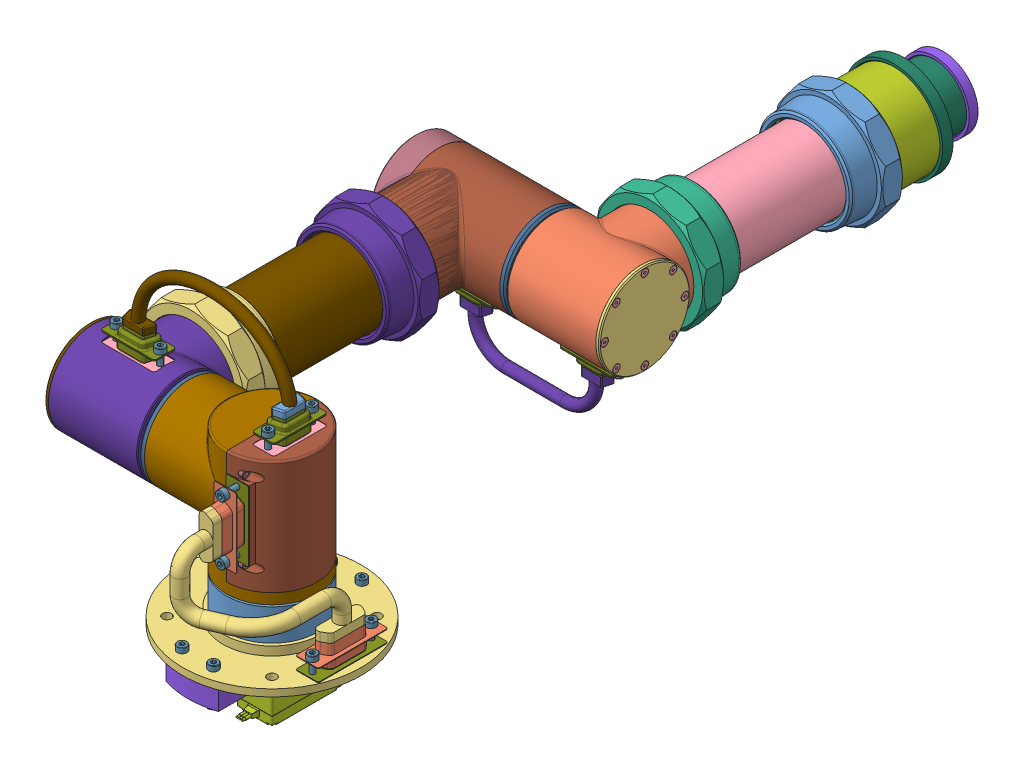
SolidWorks assembly manipulator, configuration По умолчанию. Lengths in mm.
Overall size (186.37 193.67 454.51).
208 component instances, 77 part files, 63 mates.
Components (placement in the parent):
- link_0-1: link_0 [По умолчанию] at origin size (102 73 102)
  - shell_0-2: shell_0 [По умолчанию] x (-1 0 0) z (0 -1 0) size (52 52 23)
  - sleave_external_0-1: sleave_external_0 [00] at (0 12 0) x (0 -1 0) z (0.129917 0 0.991525) size (3 42 42)
  - flange_0-1: flange_0 [По умолчанию] at (0 -4 0) size (102 9 102)
  - shaft_0-1: shaft_0 [00] at (0 -4 0) x (0 -1 0) z (0 0 -1) size (31 32 32)
  - servo_flange-1: servo_flange [По умолчанию] at (0 -1.5 0) x (-0.707107 0 0.707107) z (0.707107 0 0.707107) size (20 4.5 20)
  - screw_M3x8(DIN912)-1: screw_M3x8(DIN912) [По умолчанию] at (4.9497 -6 4.9497) x (-0.866025 0 -0.5) z (0 -1 0) size (4.6 4.6 10)
  - screw_M3x8(DIN912)-2: screw_M3x8(DIN912) [По умолчанию] at (-4.9497 -6 4.9497) x (0.5 0 -0.866025) z (0 -1 0) size (4.6 4.6 10)
  - screw_M3x8(DIN912)-3: screw_M3x8(DIN912) [По умолчанию] at (-4.9497 -6 -4.9497) x (0.866025 0 0.5) z (0 -1 0) size (4.6 4.6 10)
  - screw_M3x8(DIN912)-4: screw_M3x8(DIN912) [По умолчанию] at (4.9497 -6 -4.9497) x (-0.5 0 0.866025) z (0 -1 0) size (4.6 4.6 10)
  - servo_MG995-1: servo_MG995 [По умолчанию] at (0 -46 -10) x (0 0 1) z (0 1 0) size (55.5 20 44.57)
  - servo_lock-1: servo_lock [По умолчанию] at (0 -17 0) x (-1 0 0) z (0 0 -1) size (30 13 96)
  - screw_M4x14(DIN912)-1: screw_M4x14(DIN912) [По умолчанию] at (5 -23 14) x (0.91175 0 0.410745) z (0 -1 0) size (7 7 18)
  - ГайкаM4(DIN936)-1: ГайкаM4(DIN936) [По умолчанию] at (5 -9 14) size (7 2.2 8.08)
  - screw_M4x14(DIN912)-2: screw_M4x14(DIN912) [По умолчанию] at (-5 -23 14) x (0.91175 0 0.410745) z (0 -1 0) size (7 7 18)
  - screw_M4x14(DIN912)-3: screw_M4x14(DIN912) [По умолчанию] at (5 -23 -34) x (0.91175 0 0.410745) z (0 -1 0) size (7 7 18)
  - screw_M4x14(DIN912)-4: screw_M4x14(DIN912) [По умолчанию] at (-5 -23 -34) x (0.91175 0 0.410745) z (0 -1 0) size (7 7 18)
  - ГайкаM4(DIN936)-2: ГайкаM4(DIN936) [По умолчанию] at (-5 -9 14) size (7 2.2 8.08)
  - ГайкаM4(DIN936)-3: ГайкаM4(DIN936) [По умолчанию] at (5 -9 -34) size (7 2.2 8.08)
  - ГайкаM4(DIN936)-4: ГайкаM4(DIN936) [По умолчанию] at (-5 -9 -34) size (7 2.2 8.08)
  - bearing_6905-2RS_0-1: bearing_6905-2RS_0 [00] at (0 21 0) x (0 -1 0) z (-0.000456 0 -1) size (9 42 42)
  - sleave_internal_0-1: sleave_internal_0 [00] at (0 12 0) x (0 -1 0) z (0.154614 0 0.987975) size (3 29 29)
  - bearing_6905-2RS_0-2: bearing_6905-2RS_0 [00] at (0 9 0) x (0 -1 0) z (-0.000456 0 -1) size (9 42 42)
  - circlip for shafts normal_din-1: circlip for shafts normal_din [Circlip DIN 471 - 25 x 1.2] x (0.999946 0 -0.010391) z (0 1 0) size (28.33 31.3 1.2)
  - socket head cap screw_din-1: socket head cap screw_din [DIN 912 M2.5 x 10 --- 10N] at (11.75 -6.5 20.3516) x (0 1 0) z (-0.355215 0 0.934785) size (12.5 4.5 4.5)
  - socket head cap screw_din-2: socket head cap screw_din [DIN 912 M2.5 x 10 --- 10N] at (-11.75 -6.5 20.3516) x (0 1 0) z (-0.987155 0 0.159767) size (12.5 4.5 4.5)
  - socket head cap screw_din-3: socket head cap screw_din [DIN 912 M2.5 x 10 --- 10N] at (-23.5 -6.5 0) x (0 1 0) z (-0.631939 0 -0.775018) size (12.5 4.5 4.5)
  - socket head cap screw_din-4: socket head cap screw_din [DIN 912 M2.5 x 10 --- 10N] at (-11.75 -6.5 -20.3516) x (0 1 0) z (0.355215 0 -0.934785) size (12.5 4.5 4.5)
  - socket head cap screw_din-5: socket head cap screw_din [DIN 912 M2.5 x 10 --- 10N] at (11.75 -6.5 -20.3516) x (0 1 0) z (0.987155 0 -0.159767) size (12.5 4.5 4.5)
  - socket head cap screw_din-6: socket head cap screw_din [DIN 912 M2.5 x 10 --- 10N] at (23.5 -6.5 0) x (0 1 0) z (0.631939 0 0.775018) size (12.5 4.5 4.5)
  - socket head cap screw_din-7: socket head cap screw_din [DIN 912 M3 x 20 --- 20N] at (9 3 42.5) x (0 -1 0) z (1 0 0) size (23 5.5 5.5)
  - hex thin nut gradeb_din-1: hex thin nut gradeb_din [Hexagon Nut ISO 4036 - M3 - N] at (9 -18.8 42.5) x (0.546938 0 -0.837173) z (0 -1 0) size (5.5 6.35 1.8)
  - socket head cap screw_din-8: socket head cap screw_din [DIN 912 M3 x 20 --- 20N] at (9 3 -42.5) x (0 -1 0) z (1 0 0) size (23 5.5 5.5)
  - socket head cap screw_din-9: socket head cap screw_din [DIN 912 M3 x 20 --- 20N] at (-9 3 42.5) x (0 -1 0) z (1 0 0) size (23 5.5 5.5)
  - socket head cap screw_din-10: socket head cap screw_din [DIN 912 M3 x 20 --- 20N] at (-9 3 -42.5) x (0 -1 0) z (1 0 0) size (23 5.5 5.5)
  - hex thin nut gradeb_din-2: hex thin nut gradeb_din [Hexagon Nut ISO 4036 - M3 - N] at (9 -18.8 -42.5) x (0.546938 0 -0.837173) z (0 -1 0) size (5.5 6.35 1.8)
  - hex thin nut gradeb_din-3: hex thin nut gradeb_din [Hexagon Nut ISO 4036 - M3 - N] at (-9 -18.8 42.5) x (0.546938 0 -0.837173) z (0 -1 0) size (5.5 6.35 1.8)
  - hex thin nut gradeb_din-4: hex thin nut gradeb_din [Hexagon Nut ISO 4036 - M3 - N] at (-9 -18.8 -42.5) x (0.546938 0 -0.837173) z (0 -1 0) size (5.5 6.35 1.8)
  - DB15_F-1: DB15_F [По умолчанию] at (38.6 6.31 9.695) x (0 0 -1) z (1 0 0) size (40 15.72 13)
- link_2-1: link_2 [00] at (-56 68 0) x (0 0 -1) z (-1 0 0) size (248.92 91.41 97.96)
  - link_2_part_1-1: link_2_part_1 [00] at origin size (82.24 91.41 89.92)
    - case_2_part_1-1: case_2_part_1 [По умолчанию] at origin size (79.09 52.19 55.06)
    - case_cover_2_part_1-1: case_cover_2_part_1 [По умолчанию] at (0 0 46) size (52 52 2)
    - screw_M2x8(DIN7991)_2_part_1-1: screw_M2x8(DIN7991)_2_part_1 [Default] at (-23 0 46.8) x (0 0 -1) z (1 0 0) size (8 4 4)
    - screw_M2x8(DIN7991)_2_part_1-2: screw_M2x8(DIN7991)_2_part_1 [Default] at (-16.2635 16.2635 46.8) x (0 0 -1) z (1 0 0) size (8 4 4)
    - screw_M2x8(DIN7991)_2_part_1-3: screw_M2x8(DIN7991)_2_part_1 [Default] at (0 23 46.8) x (0 0 -1) z (1 0 0) size (8 4 4)
    - screw_M2x8(DIN7991)_2_part_1-4: screw_M2x8(DIN7991)_2_part_1 [Default] at (16.2635 16.2635 46.8) x (0 0 -1) z (1 0 0) size (8 4 4)
    - screw_M2x8(DIN7991)_2_part_1-5: screw_M2x8(DIN7991)_2_part_1 [Default] at (23 0 46.8) x (0 0 -1) z (1 0 0) size (8 4 4)
    - screw_M2x8(DIN7991)_2_part_1-6: screw_M2x8(DIN7991)_2_part_1 [Default] at (16.2635 -16.2635 46.8) x (0 0 -1) z (1 0 0) size (8 4 4)
    - screw_M2x8(DIN7991)_2_part_1-7: screw_M2x8(DIN7991)_2_part_1 [Default] at (0 -23 46.8) x (0 0 -1) z (1 0 0) size (8 4 4)
    - screw_M2x8(DIN7991)_2_part_1-8: screw_M2x8(DIN7991)_2_part_1 [Default] at (-16.2635 -16.2635 46.8) x (0 0 -1) z (1 0 0) size (8 4 4)
    - bolt_M3x8(DIN912)_2_part_1-1: bolt_M3x8(DIN912)_2_part_1 [По умолчанию] at (10 0 2) size (4.6 4.6 10)
    - bolt_M3x8(DIN912)_2_part_1-3: bolt_M3x8(DIN912)_2_part_1 [По умолчанию] at (0 -10 2) size (4.6 4.6 10)
    - bolt_M3x8(DIN912)_2_part_1-4: bolt_M3x8(DIN912)_2_part_1 [По умолчанию] at (-10 0 2) size (4.6 4.6 10)
    - bolt_M3x8(DIN912)_2_part_1-5: bolt_M3x8(DIN912)_2_part_1 [По умолчанию] at (0 10 2) size (4.6 4.6 10)
    - collet_nut_2_part_1-4: collet_nut_2_part_1 [По умолчанию] at (42.2 0 20.5) x (0 -0.587785 0.809017) z (0 0.809017 0.587785) size (61.55 26.55 68.27)
    - A_DB9-1: A_DB9 [По умолчанию] at (-16.7349 -2.8234 29.5281) x (0 0 -1) z (0 -1 0) size (30.9 12.5 15.5)
  - link_2_part_2-2: link_2_part_2 [00] at (186 0 -1.5) x (0 0 1) z (-0.003987 0.999992 0) size (83.78 107.15 73.54)
    - shaft_2-1: shaft_2 [00] x (1 0 0) z (0 0.707107 0.707107) size (31 32 32)
    - bearing_6905-2RS-1: bearing_6905-2RS [00] at (-25 0 0) size (9 42 42)
    - sleave_internal_2-1: sleave_internal_2 [00] at (-16 0 0) size (3 29 29)
    - sleave_external_2-2: sleave_external_2 [00] at (-16 0 0) size (3 42 42)
    - bearing_6905-2RS-2: bearing_6905-2RS [00] at (-13 0 0) size (9 42 42)
    - servo_flange_2-1: servo_flange_2 [По умолчанию] at (-2.5 0 0) x (0 -1 0) z (0 0 1) size (20 4.5 20)
    - bearing_cover_2-1: bearing_cover_2 [00] at (-28 0 0) x (1 0 0) z (0 0.709921 0.704282) size (3.19 52 52)
    - case_2_part_2-3: case_2_part_2 [00] at (-25 0 0) x (1 0 0) z (0 0.003987 0.999992) size (72 93 52)
    - servo_MG995-2: servo_MG995 [По умолчанию] at (42 -9.9999 0.0399) x (0 0.999992 -0.003987) z (-1 0 0) size (55.5 20 44.57)
    - screw_M2x10(DIN7991)_2_part_2-2: screw_M2x10(DIN7991)_2_part_2 [Default] at (-26.8 22.9998 -0.0917) x (1 0 0) z (0 -0.003987 -0.999992) size (10 4 4)
    - case_cover_2_part_2-2: case_cover_2_part_2 [00] at (22 0 0) x (0 -0.999992 0.003987) z (0 0.003987 0.999992) size (63 17.67 52)
    - servo_lock_2-1: servo_lock_2 [00] at (8 0 0) x (0 -0.003987 -0.999992) z (1 0 0) size (50 59.91 34)
    - bolt_M3x8(DIN912)-1: bolt_M3x8(DIN912) [По умолчанию] at (17 14.0198 4.9441) x (0 -0.003987 -0.999992) z (1 0 0) size (4.6 4.6 10)
    - screw_M2x10(DIN7991)_2_part_2-13: screw_M2x10(DIN7991)_2_part_2 [Default] at (-26.8 16.3282 16.1985) x (1 0 0) z (0 -0.003987 -0.999992) size (10 4 4)
    - screw_M2x10(DIN7991)_2_part_2-14: screw_M2x10(DIN7991)_2_part_2 [Default] at (-26.8 0.0917 22.9998) x (1 0 0) z (0 -0.003987 -0.999992) size (10 4 4)
    - screw_M2x10(DIN7991)_2_part_2-15: screw_M2x10(DIN7991)_2_part_2 [Default] at (-26.8 -16.1985 16.3282) x (1 0 0) z (0 -0.003987 -0.999992) size (10 4 4)
    - screw_M2x10(DIN7991)_2_part_2-16: screw_M2x10(DIN7991)_2_part_2 [Default] at (-26.8 -22.9998 0.0917) x (1 0 0) z (0 -0.003987 -0.999992) size (10 4 4)
    - screw_M2x10(DIN7991)_2_part_2-17: screw_M2x10(DIN7991)_2_part_2 [Default] at (-26.8 -16.3282 -16.1985) x (1 0 0) z (0 -0.003987 -0.999992) size (10 4 4)
    - screw_M2x10(DIN7991)_2_part_2-18: screw_M2x10(DIN7991)_2_part_2 [Default] at (-26.8 -0.0917 -22.9998) x (1 0 0) z (0 -0.003987 -0.999992) size (10 4 4)
    - screw_M2x10(DIN7991)_2_part_2-19: screw_M2x10(DIN7991)_2_part_2 [Default] at (-26.8 16.1985 -16.3282) x (1 0 0) z (0 -0.003987 -0.999992) size (10 4 4)
    - bolt_M3x8(DIN912)-10: bolt_M3x8(DIN912) [По умолчанию] at (2 -7 0) x (0 -0.868012 -0.496543) z (1 0 0) size (4.6 4.6 10)
    - bolt_M3x8(DIN912)-11: bolt_M3x8(DIN912) [По умолчанию] at (2 0 7) x (0 -0.868012 -0.496543) z (1 0 0) size (4.6 4.6 10)
    - bolt_M3x8(DIN912)-12: bolt_M3x8(DIN912) [По умолчанию] at (2 7 0) x (0 -0.868012 -0.496543) z (1 0 0) size (4.6 4.6 10)
    - bolt_M3x8(DIN912)-13: bolt_M3x8(DIN912) [По умолчанию] at (2 0 -7) x (0 -0.868012 -0.496543) z (1 0 0) size (4.6 4.6 10)
    - bolt_M3x8(DIN912)-15: bolt_M3x8(DIN912) [По умолчанию] at (17 13.98 -5.0558) x (0 -0.003987 -0.999992) z (1 0 0) size (4.6 4.6 10)
    - bolt_M3x8(DIN912)-16: bolt_M3x8(DIN912) [По умолчанию] at (17 -33.9798 5.1355) x (0 -0.003987 -0.999992) z (1 0 0) size (4.6 4.6 10)
    - bolt_M3x8(DIN912)-17: bolt_M3x8(DIN912) [По умолчанию] at (17 -34.0197 -4.8644) x (0 -0.003987 -0.999992) z (1 0 0) size (4.6 4.6 10)
    - screw_M2x16(DIN7991)_2_part_2-6: screw_M2x16(DIN7991)_2_part_2 [Default] at (48.3 0.0917 22.9998) x (-1 0 0) z (0 -0.003987 -0.999992) size (16 4 4)
    - screw_M2x16(DIN7991)_2_part_2-7: screw_M2x16(DIN7991)_2_part_2 [Default] at (48.3 16.3282 16.1985) x (-1 0 0) z (0 -0.003987 -0.999992) size (16 4 4)
    - screw_M2x16(DIN7991)_2_part_2-8: screw_M2x16(DIN7991)_2_part_2 [Default] at (48.3 22.9998 -0.0917) x (-1 0 0) z (0 -0.003987 -0.999992) size (16 4 4)
    - screw_M2x16(DIN7991)_2_part_2-9: screw_M2x16(DIN7991)_2_part_2 [Default] at (48.3 16.1985 -16.3282) x (-1 0 0) z (0 -0.003987 -0.999992) size (16 4 4)
    - screw_M2x16(DIN7991)_2_part_2-10: screw_M2x16(DIN7991)_2_part_2 [Default] at (48.3 -0.0917 -22.9998) x (-1 0 0) z (0 -0.003987 -0.999992) size (16 4 4)
    - collet_nut_2_part_2-1: collet_nut_2_part_2 [По умолчанию] at (22 -56.1996 0.2241) x (-1 0 0) z (0 0.003987 0.999992) size (61.55 26.55 68.27)
    - circlip for shafts normal_din-1: circlip for shafts normal_din [Circlip DIN 471 - 25 x 1.2] at (-4 0 0) x (0 0.144431 0.989515) z (-1 0 0) size (28.33 31.3 1.2)
    - A_DB9-1: A_DB9 [По умолчанию] at (5.9719 -16.7195 3.89) x (1 0 0) z (0 0.003987 0.999992) size (30.9 12.5 15.5)
  - pipe_2-1: pipe_2 [По умолчанию] at (146 0 20.5) x (-1 0 0) z (0 -0.924225 -0.381849) size (120 45 45)
  - провод^link_2-1: провод^link_2 [По умолчанию] at origin size (210 37.6 33.75) (virtual)
- link_3-1: link_3 [00] at (-20.5 68 -186) x (0 0 -1) z (1 0 0) size (231.3 129.82 129.82)
  - link_3_part_1-1: link_3_part_1 [00] at origin size (82.24 68.27 61.55)
    - case_3_part_1-2: case_3_part_1 [По умолчанию] at origin size (79.09 52.19 55.06)
    - case_cover_3_part_1-1: case_cover_3_part_1 [По умолчанию] at (0 0 46) size (52 52 2)
    - screw_M2x8(DIN7991)_3_part_1-1: screw_M2x8(DIN7991)_3_part_1 [Default] at (-23 0 46.8) x (0 0 -1) z (1 0 0) size (8 4 4)
    - screw_M2x8(DIN7991)_3_part_1-2: screw_M2x8(DIN7991)_3_part_1 [Default] at (-16.2635 16.2635 46.8) x (0 0 -1) z (1 0 0) size (8 4 4)
    - screw_M2x8(DIN7991)_3_part_1-3: screw_M2x8(DIN7991)_3_part_1 [Default] at (0 23 46.8) x (0 0 -1) z (1 0 0) size (8 4 4)
    - screw_M2x8(DIN7991)_3_part_1-4: screw_M2x8(DIN7991)_3_part_1 [Default] at (16.2635 16.2635 46.8) x (0 0 -1) z (1 0 0) size (8 4 4)
    - screw_M2x8(DIN7991)_3_part_1-5: screw_M2x8(DIN7991)_3_part_1 [Default] at (23 0 46.8) x (0 0 -1) z (1 0 0) size (8 4 4)
    - screw_M2x8(DIN7991)_3_part_1-6: screw_M2x8(DIN7991)_3_part_1 [Default] at (16.2635 -16.2635 46.8) x (0 0 -1) z (1 0 0) size (8 4 4)
    - screw_M2x8(DIN7991)_3_part_1-7: screw_M2x8(DIN7991)_3_part_1 [Default] at (0 -23 46.8) x (0 0 -1) z (1 0 0) size (8 4 4)
    - screw_M2x8(DIN7991)_3_part_1-8: screw_M2x8(DIN7991)_3_part_1 [Default] at (-16.2635 -16.2635 46.8) x (0 0 -1) z (1 0 0) size (8 4 4)
    - bolt_M3x8(DIN912)_3_part_1-1: bolt_M3x8(DIN912)_3_part_1 [По умолчанию] at (10 0 2) size (4.6 4.6 10)
    - bolt_M3x8(DIN912)_3_part_1-2: bolt_M3x8(DIN912)_3_part_1 [По умолчанию] at (0 -10 2) size (4.6 4.6 10)
    - bolt_M3x8(DIN912)_3_part_1-3: bolt_M3x8(DIN912)_3_part_1 [По умолчанию] at (-10 0 2) size (4.6 4.6 10)
    - bolt_M3x8(DIN912)_3_part_1-4: bolt_M3x8(DIN912)_3_part_1 [По умолчанию] at (0 10 2) size (4.6 4.6 10)
    - A_DB9-2: A_DB9 [По умолчанию] at (-16.7349 -3.8234 29.5281) x (0 0 -1) z (0 -1 0) size (30.9 12.5 15.5)
    - collet_nut_3_part_1-2: collet_nut_3_part_1 [По умолчанию] at (42.2 0 20.5) x (0 0 -1) z (0 -1 0) size (61.55 26.55 68.27)
  - link_3_part_2-1: link_3_part_2 [По умолчанию] at (135 0 20.5) x (0 0.707107 -0.707107) z (1 0 0) size (91.8 91.8 86.74)
    - case_3_part_2-2: case_3_part_2 [По умолчанию] at origin size (52.23 52.12 50.29)
    - case_cover_3_part_2-1: case_cover_3_part_2 [По умолчанию] at (0 0 60.3) x (-0.707107 -0.707107 0) z (0 0 1) size (40 40 5)
    - servo_MG90S-1: servo_MG90S [Default] at (-5.25 0 12) x (1 0 0) z (0 -1 0) size (32.2 32.5 12.4)
    - servo_flange_3-2: servo_flange_3 [По умолчанию] at (0 0 45.3) x (0.074504 -0.997221 0) z (0 0 -1) size (17 17 9)
    - bearing_6803-1: bearing_6803 [По умолчанию] at (0 0 55.3) x (0.713069 0.701094 0) z (0 0 1) size (26 26 5)
    - bearing_6803-2: bearing_6803 [По умолчанию] at (0 0 53.8) x (-0.923728 -0.383049 0) z (0 0 -1) size (26 26 5)
    - shaft_3_part_2-1: shaft_3_part_2 [По умолчанию] at (0 0 45.3) x (-0.074504 0.997221 0) z (0.997221 0.074504 0) size (20 25 20)
    - ext_sleeve_3_part_2-1: ext_sleeve_3_part_2 [По умолчанию] at (0 0 55.3) x (-0.923728 -0.383049 0) z (0 0 -1) size (26 26 1.5)
    - int_sleeve_3_part_2-1: int_sleeve_3_part_2 [По умолчанию] at (0 0 55.3) x (-0.923728 -0.383049 0) z (0 0 -1) size (19 19 1.5)
    - nozzle_3_part_2-1: nozzle_3_part_2 [По умолчанию] at (0 0 37) x (0.707107 0.707107 0) z (0.707107 -0.707107 0) size (56 25.3 56)
    - screw_M2x8(DIN963)-1: screw_M2x8(DIN963) [По умолчанию] at (-15.5563 -15.5563 40.6206) x (0 0 -1) z (-0.707107 -0.707107 0) size (8 3.8 3.77)
    - screw_M2x8(DIN963)-5: screw_M2x8(DIN963) [По умолчанию] at (10.9602 10.9602 62.9206) x (0 0 -1) z (0.707107 0.707107 0) size (8 3.8 3.77)
    - nut_M1.6(DIN934)-1: nut_M1.6(DIN934) [По умолчанию] at (-19.1 0 34.8) x (1 0 0) z (0 0 -1) size (2.95 3.41 1.3)
    - screw_M1.6x10(DIN921)-1: screw_M1.6x10(DIN921) [По умолчанию] at (-19.1 0 24.9) x (0 0 1) z (-1 0 0) size (11.6 3 3)
    - nut_M1.6(DIN934)-2: nut_M1.6(DIN934) [По умолчанию] at (8.6 0 34.8) x (1 0 0) z (0 0 -1) size (2.95 3.41 1.3)
    - screw_M1.6x10(DIN921)-2: screw_M1.6x10(DIN921) [По умолчанию] at (8.6 0 24.9) x (0 0 1) z (-0.053634 0.998561 0) size (11.6 3 3)
    - screw_M2x8(DIN963)-2: screw_M2x8(DIN963) [По умолчанию] at (-15.5563 15.5563 40.6206) x (0 0 -1) z (-0.707107 0.707107 0) size (8 3.8 3.77)
    - screw_M2x8(DIN963)-3: screw_M2x8(DIN963) [По умолчанию] at (15.5563 15.5563 40.6206) x (0 0 -1) z (0.707107 0.707107 0) size (8 3.8 3.77)
    - screw_M2x8(DIN963)-4: screw_M2x8(DIN963) [По умолчанию] at (15.5563 -15.5563 40.6206) x (0 0 -1) z (0.707107 -0.707107 0) size (8 3.8 3.77)
    - screw_M2x8(DIN963)-6: screw_M2x8(DIN963) [По умолчанию] at (10.9602 -10.9602 62.9206) x (0 0 -1) z (0.707107 -0.707107 0) size (8 3.8 3.77)
    - screw_M2x8(DIN963)-7: screw_M2x8(DIN963) [По умолчанию] at (-10.9602 -10.9602 62.9206) x (0 0 -1) z (-0.707107 -0.707107 0) size (8 3.8 3.77)
    - screw_M2x8(DIN963)-8: screw_M2x8(DIN963) [По умолчанию] at (-10.9602 10.9602 62.9206) x (0 0 -1) z (-0.707107 0.707107 0) size (8 3.8 3.77)
    - collet_nut_3_part_2-2: collet_nut_3_part_2 [По умолчанию] at (0 0 -2.4) x (-0.707107 0.707107 0) z (-0.707107 -0.707107 0) size (61.55 26.55 68.27)
    - Деталь1^link_3_part_2-1: Деталь1^link_3_part_2 [По умолчанию] at origin (virtual)
    - hex bolt gradeab_din-1: hex bolt gradeab_din [DIN EN 24014 - M2 x 16 x 10-N] at (-0.447 5.9833 41.9) x (0 0 1) z (-0.964999 -0.262255 0) size (17.4 4.62 4)
    - hex bolt gradeab_din-2: hex bolt gradeab_din [DIN EN 24014 - M2 x 16 x 10-N] at (5.9833 0.447 41.9) x (0 0 1) z (-0.262255 0.964999 0) size (17.4 4.62 4)
    - hex bolt gradeab_din-3: hex bolt gradeab_din [DIN EN 24014 - M2 x 16 x 10-N] at (0.447 -5.9833 41.9) x (0 0 1) z (0.964999 0.262255 0) size (17.4 4.62 4)
    - hex bolt gradeab_din-4: hex bolt gradeab_din [DIN EN 24014 - M2 x 16 x 10-N] at (-5.9833 -0.447 41.9) x (0 0 1) z (0.262255 -0.964999 0) size (17.4 4.62 4)
    - retaining_ring-1: retaining_ring [По умолчанию] at (0 0 47.2) size (19 21 1.5)
  - pipe_3-1: pipe_3 [По умолчанию] at (26 0 20.5) x (1 0 0) z (0 -0.068443 0.997655) size (120 45 45)
  - Деталь1^link_3-1: Деталь1^link_3 [По умолчанию] at origin size (155.92 29.47 12.17) (virtual)
- link_1-2: link_1 [00] at (26.6423 95 0) size (79 90.5 58.36)
  - shaft_1-1: shaft_1 [00] at (-48.6423 -27 0) x (1 0 0) z (0 0.707107 0.707107) size (31 32 32)
  - servo_flange-1: servo_flange [По умолчанию] at (-51.1423 -27 0) x (0 1 0) z (0 0 -1) size (20 4.5 20)
  - bearing_6905-2RS-1: bearing_6905-2RS [00] at (-73.6423 -27 0) size (9 42 42)
  - bearing_6905-2RS-2: bearing_6905-2RS [00] at (-61.6423 -27 0) size (9 42 42)
  - sleave_external_1-1: sleave_external_1 [00] at (-64.6423 -27 0) size (3 42 42)
  - sleave_internal_1-1: sleave_internal_1 [00] at (-64.6423 -27 0) size (3 29 29)
  - case_1-1: case_1 [По умолчанию] at (-26.6423 -71 0) x (0 0 -1) z (1 0 0) size (52 71.51 73)
  - servo_MG995-1: servo_MG995 [По умолчанию] at (-6.1423 -37 0) x (0 1 0) z (-1 0 0) size (55.5 20 44.57)
  - bearing_cover_1-1: bearing_cover_1 [00] at (-76.6423 -27 0) x (1 0 0) z (0 -1 0) size (3.19 52 52)
  - case_cover_1-2: case_cover_1 [По умолчанию] at (-26.6423 -65 0) x (0 0 -1) z (1 0 0) size (52 65 27.19)
  - slotted countersunk flat head screw_iso-39: slotted countersunk flat head screw_iso [ISO 2009 - M2 x 8 - 8N] at (-76.6423 -27 23) x (1 0 0) z (0 -0.076481 0.997071) size (8 3.8 3.77)
  - slotted countersunk flat head screw_iso-40: slotted countersunk flat head screw_iso [ISO 2009 - M2 x 8 - 8N] at (-76.6423 -43.2635 16.2635) x (1 0 0) z (0 -0.759116 0.650956) size (8 3.8 3.77)
  - slotted countersunk flat head screw_iso-41: slotted countersunk flat head screw_iso [ISO 2009 - M2 x 8 - 8N] at (-76.6423 -50 0) x (1 0 0) z (0 -0.997071 -0.076481) size (8 3.8 3.77)
  - slotted countersunk flat head screw_iso-42: slotted countersunk flat head screw_iso [ISO 2009 - M2 x 8 - 8N] at (-76.6423 -43.2635 -16.2635) x (1 0 0) z (0 -0.650956 -0.759116) size (8 3.8 3.77)
  - slotted countersunk flat head screw_iso-43: slotted countersunk flat head screw_iso [ISO 2009 - M2 x 8 - 8N] at (-76.6423 -27 -23) x (1 0 0) z (0 0.076481 -0.997071) size (8 3.8 3.77)
  - slotted countersunk flat head screw_iso-44: slotted countersunk flat head screw_iso [ISO 2009 - M2 x 8 - 8N] at (-76.6423 -10.7365 -16.2635) x (1 0 0) z (0 0.759116 -0.650956) size (8 3.8 3.77)
  - slotted countersunk flat head screw_iso-45: slotted countersunk flat head screw_iso [ISO 2009 - M2 x 8 - 8N] at (-76.6423 -4 0) x (1 0 0) z (0 0.997071 0.076481) size (8 3.8 3.77)
  - slotted countersunk flat head screw_iso-46: slotted countersunk flat head screw_iso [ISO 2009 - M2 x 8 - 8N] at (-76.6423 -10.7365 16.2635) x (1 0 0) z (0 0.650956 0.759116) size (8 3.8 3.77)
  - socket head cap screw_iso-25: socket head cap screw_iso [ISO 4762 M2.5 x 10 - 10N] at (-18.1423 -8.5 23) x (-1 0 0) z (0 -0.877208 -0.48011) size (12.5 4.5 4.5)
  - socket head cap screw_iso-29: socket head cap screw_iso [ISO 4762 M2.5 x 10 - 10N] at (-18.1423 -53.5 23) x (-1 0 0) z (0 -0.877208 -0.48011) size (12.5 4.5 4.5)
  - socket head cap screw_iso-27: socket head cap screw_iso [ISO 4762 M2.5 x 10 - 10N] at (-18.1423 -8.5 -23) x (-1 0 0) z (0 -0.877208 -0.48011) size (12.5 4.5 4.5)
  - socket head cap screw_iso-28: socket head cap screw_iso [ISO 4762 M2.5 x 10 - 10N] at (-18.1423 -53.5 -23) x (-1 0 0) z (0 -0.877208 -0.48011) size (12.5 4.5 4.5)
  - socket head cap screw_iso-20: socket head cap screw_iso [ISO 4762 M3 x 8 - 8N] at (-30.1423 -13 5) x (-1 0 0) z (0 0.270929 0.962599) size (11 5.5 5.5)
  - socket head cap screw_iso-24: socket head cap screw_iso [ISO 4762 M3 x 8 - 8N] at (-30.1423 -61 5) x (-1 0 0) z (0 0.270929 0.962599) size (11 5.5 5.5)
  - socket head cap screw_iso-22: socket head cap screw_iso [ISO 4762 M3 x 8 - 8N] at (-30.1423 -13 -5) x (-1 0 0) z (0 0.270929 0.962599) size (11 5.5 5.5)
  - socket head cap screw_iso-23: socket head cap screw_iso [ISO 4762 M3 x 8 - 8N] at (-30.1423 -61 -5) x (-1 0 0) z (0 0.270929 0.962599) size (11 5.5 5.5)
  - socket head cap screw_iso-4: socket head cap screw_iso [ISO 4762 M3 x 8 - 8N] at (-45.6423 -27 7) x (-1 0 0) z (0 0.294157 -0.955757) size (11 5.5 5.5)
  - socket head cap screw_iso-5: socket head cap screw_iso [ISO 4762 M3 x 8 - 8N] at (-45.6423 -34 0) x (-1 0 0) z (0 0.955757 0.294157) size (11 5.5 5.5)
  - socket head cap screw_iso-6: socket head cap screw_iso [ISO 4762 M3 x 8 - 8N] at (-45.6423 -27 -7) x (-1 0 0) z (0 -0.294157 0.955757) size (11 5.5 5.5)
  - socket head cap screw_iso-7: socket head cap screw_iso [ISO 4762 M3 x 8 - 8N] at (-45.6423 -20 0) x (-1 0 0) z (0 -0.955757 -0.294157) size (11 5.5 5.5)
  - circlip for shafts normal_din-1: circlip for shafts normal_din [Circlip DIN 471 - 25 x 1.2] at (-53.1423 -27 0) x (0 0 -1) z (-1 0 0) size (28.33 31.3 1.2) (hidden)
  - A_DB9-1: A_DB9 [По умолчанию] at (0.3425 -22.1766 9.0281) x (0 0 -1) z (0 1 0) size (30.9 12.5 15.5)
  - socket countersunk head screw_din-1: socket countersunk head screw_din [DIN 7991 - M3 x 20 --- 16.8N] at (-16.6423 -65 0) x (0 -1 0) z (-0.98859 0 0.150633) size (20 5.7 5.7)
  - socket countersunk head screw_din-6: socket countersunk head screw_din [DIN 7991 - M3 x 20 --- 16.8N] at (-26.6423 -65 -10) x (0 -1 0) z (0.150633 0 0.98859) size (20 5.7 5.7)
  - socket countersunk head screw_din-3: socket countersunk head screw_din [DIN 7991 - M3 x 20 --- 16.8N] at (-36.6423 -65 0) x (0 -1 0) z (0.98859 0 -0.150633) size (20 5.7 5.7)
  - socket countersunk head screw_din-4: socket countersunk head screw_din [DIN 7991 - M3 x 20 --- 16.8N] at (-26.6423 -65 10) x (0 -1 0) z (-0.150633 0 -0.98859) size (20 5.7 5.7)
  - DB15_F-1: DB15_F [По умолчанию] at (-21.5423 -40.695 32.31) x (0 1 0) z (1 0 0) size (40 15.72 13)
  - провода^link_1-1: провода^link_1 [По умолчанию] at origin size (23.78 38.41 28.01) (virtual)
- A_DB9 - MALE-1: A_DB9 - MALE [По умолчанию] at (-9.0281 14.4234 -169.2651) x (1 0 0) z (0 1 0) size (30.9 12.5 15.5)
- A_DB9 - MALE-2: A_DB9 - MALE [По умолчанию] at (-78.5281 14.4234 -169.2651) x (1 0 0) z (0 1 0) size (30.9 12.5 15.5)
- провод 2-3^manipulator-1: провод 2-3^manipulator [По умолчанию] at origin size (84.34 28 6.5) (virtual)
- socket head cap screw_din-10: socket head cap screw_din [DIN 912 M3 x 16 --- 16N] at (12.5 32.6 -186) x (0 1 0) z (-0.333637 0 0.942702) size (19 5.5 5.5)
- socket head cap screw_din-11: socket head cap screw_din [DIN 912 M3 x 16 --- 16N] at (-12.5 32.6 -186) x (0 1 0) z (-0.85276 0 0.522303) size (19 5.5 5.5)
- socket head cap screw_din-12: socket head cap screw_din [DIN 912 M3 x 16 --- 16N] at (-57 32.6 -186) x (0 1 0) z (-0.094976 0 0.99548) size (19 5.5 5.5)
- socket head cap screw_din-13: socket head cap screw_din [DIN 912 M3 x 16 --- 16N] at (-82 32.6 -186) x (0 1 0) z (-0.517198 0 0.855866) size (19 5.5 5.5)
- A_DB9 - MALE-3: A_DB9 - MALE [По умолчанию] at (-67.4719 120.5766 16.7349) x (-1 0 0) z (0 -1 0) size (30.9 12.5 15.5)
- A_DB9 - MALE-4: A_DB9 - MALE [По умолчанию] at (26.9849 122.5766 -9.0281) x (0 0 1) z (0 -1 0) size (30.9 12.5 15.5)
- wire_1-1: wire_1 [По умолчанию] at (-76.5 109.1 0) x (-1 0 0) z (0 -1 0) size (97.59 6.5 42.57)
- connector_1-1: connector_1 [По умолчанию] at (10.25 111.1 0) x (0 0 1) z (0 -1 0) size (15.19 6.5 4)
- socket head cap screw_din-6: socket head cap screw_din [DIN 912 M3 x 16 --- 16N] at (-89 102.4 0) x (0 -1 0) z (0.447853 0 0.894107) size (19 5.5 5.5)
- socket head cap screw_din-7: socket head cap screw_din [DIN 912 M3 x 16 --- 16N] at (-64 102.4 0) x (0 -1 0) z (0.937749 0 0.347314) size (19 5.5 5.5)
- socket head cap screw_din-8: socket head cap screw_din [DIN 912 M3 x 16 --- 16N] at (10.25 104.4 12.5) x (0 -1 0) z (0.754954 0 0.655778) size (19 5.5 5.5)
- socket head cap screw_din-9: socket head cap screw_din [DIN 912 M3 x 16 --- 16N] at (10.25 104.4 -12.5) x (0 -1 0) z (0.999036 0 0.043895) size (19 5.5 5.5)
- DB15_M-3: DB15_M [По умолчанию] at (5.08 54.155 39.209) x (0 1 0) z (-1 0 0) size (40 15.86 13)
- DB15_M-4: DB15_M [По умолчанию] at (38.58 13.209 9.835) x (0 0 -1) z (-1 0 0) size (40 15.86 13)
- socket head cap screw_din-3: socket head cap screw_din [DIN 912 M3 x 16 --- 16N] at (6.5 80.82 36.309) x (0 0 -1) z (0.56271 -0.826654 0) size (19 5.5 5.5)
- socket head cap screw_din-4: socket head cap screw_din [DIN 912 M3 x 16 --- 16N] at (6.5 47.17 36.309) x (0 0 -1) z (0.813575 0.581461 0) size (19 5.5 5.5)
- провод 0-1^manipulator-1: провод 0-1^manipulator [По умолчанию] at origin size (41.5 63.24 75.67) (virtual)
- socket head cap screw_din-14: socket head cap screw_din [DIN 912 M3 x 16 --- 16N] at (40 10.309 -16.83) x (0 -1 0) z (0.769672 0 0.638439) size (19 5.5 5.5)
- socket head cap screw_din-15: socket head cap screw_din [DIN 912 M3 x 16 --- 16N] at (40 10.309 16.82) x (0 -1 0) z (0.892194 0 0.451653) size (19 5.5 5.5)
- hex thin nut chamfered gradeab_din-1: hex thin nut chamfered gradeab_din [Hexagon Thin Nut ISO 4035 - M3 - N] at (40 -5.8 16.82) x (0.812608 0 -0.582811) z (0 -1 0) size (5.5 6.35 1.8)
- hex thin nut chamfered gradeab_din-2: hex thin nut chamfered gradeab_din [Hexagon Thin Nut ISO 4035 - M3 - N] at (40 -5.8 -16.83) x (0.394981 0 -0.918689) z (0 -1 0) size (5.5 6.35 1.8)
Mates (geometry in assembly coordinates):
- Концентричный4: concentric anti-aligned: cylinder of link_2-1/link_2_part_2-2/case_2_part_2-3 through (-29.5 68 -186) axis (1 0 0) radius 26; cylinder of link_3-1/link_3_part_1-1/case_3_part_1-2 through (25.5 68 -186) axis (-1 0 0) radius 26
- Совпадение9: coincident anti-aligned: plane of link_2-1/link_2_part_2-2/shaft_2-1 through (-23.5 79.2685 -197.3587) normal (1 0 0); plane of link_3-1/link_3_part_1-1/case_3_part_1-2 through (-23.5 68 -186) normal (-1 0 0)
- Концентричный5: concentric anti-aligned: cylinder of link_0-1/shell_0-2 through (0 0 0) axis (0 -1 0) radius 26; cylinder of link_1-2/case_1-1 through (0 97.6815 0) axis (0 1 0) radius 26
- Концентричный6: concentric aligned: cylinder of link_2-1/link_2_part_1-1/case_2_part_1-1 through (-102 68 0) axis (1 0 0) radius 26; cylinder of link_1-2/case_1-1 through (-47 68 0) axis (1 0 0) radius 26
- Совпадение10: coincident anti-aligned: plane of link_0-1/shaft_0-1 through (-16 27 0) normal (0 1 0); plane of link_1-2/case_1-1 through (0 27 0) normal (0 -1 0)
- Совпадение11: coincident anti-aligned: plane of link_2-1/link_2_part_1-1/case_2_part_1-1 through (-53 68 0) normal (1 0 0); plane of link_1-2/shaft_1-1 through (-53 79.3137 -11.3137) normal (-1 0 0)
- Угол1: planar angle aligned: axis of link_1-2/case_1-1 through (-52.5586 68 0) axis (1 0 0); line of link_0-1/servo_lock-1 through (-15 -17 -45.5961) axis (0 0 1)
- Угол2: planar angle aligned: axis of link_2-1/pipe_2-1 through (-76.5 68 -26) axis (0 0 -1); axis of link_1-2/case_cover_1-2 through (0 84 0) axis (0 -1 0)
- Угол3: planar angle anti-aligned: axis of link_2-1/pipe_2-1 through (-76.5 68 -26) axis (0 0 -1); axis of link_3-1/pipe_3-1 through (0 68 -332) axis (0 0 1)
- Совпадение14: coincident anti-aligned: plane of link_3-1/link_3_part_1-1/A_DB9-2 through (0 36.5 -186) normal (0 -1 0); plane of A_DB9 - MALE-1 through (-8.8065 36.5 -189.275) normal (0 1 0)
- Совпадение17: coincident anti-aligned: plane of link_2-1/link_2_part_2-2/A_DB9-1 through (-69.5 36.5 -186) normal (0 -1 0); plane of A_DB9 - MALE-2 through (-78.3065 36.5 -189.275) normal (0 1 0)
- Совпадение25: coincident anti-aligned: plane of A_DB9 - MALE-1 through (0 29.9 -186) normal (0 -1 0); plane of ? through (-68.4582 29.9 -185.4704) normal (0 1 0)
- Совпадение26: coincident anti-aligned: plane of A_DB9 - MALE-1 through (0 29.9 -186) normal (0 -1 0); plane of ? through (1.0949 29.9 -186.1438) normal (0 1 0)
- Совпадение29: coincident anti-aligned: plane of link_2-1/link_2_part_1-1/A_DB9-1 through (-76.5 98.5 0) normal (0 1 0); plane of A_DB9 - MALE-3 through (-67.6935 98.5 -3.275) normal (0 -1 0)
- Совпадение32: coincident anti-aligned: plane of link_1-2/A_DB9-1 through (10.25 100.5 0) normal (0 1 0); plane of A_DB9 - MALE-4 through (6.975 100.5 -8.8065) normal (0 -1 0)
- Совпадение34: coincident anti-aligned: plane of A_DB9 - MALE-3 through (-76.5 105.1 0) normal (0 1 0); plane of wire_1-1 through (-76.5 105.1 0) normal (0 -1 0)
- Ширина1: width anti-aligned: plane of wire_1-1 through (-68.6783 105.1 -3.25) normal (0.965926 0 0.258819); plane of wire_1-1 through (-82.58 105.1 3.25) normal (-0.965926 0 0.258819); plane of A_DB9 - MALE-3 through (-82.8479 99 1.7009) normal (-0.965926 0 0.258819); plane of A_DB9 - MALE-3 through (-70.1521 99 1.7009) normal (0.965926 0 0.258819)
- Совпадение37: coincident aligned: plane of A_DB9 - MALE-3 through (-76.5 99 -3.25) normal (0 0 -1); plane of wire_1-1 through (-84.3217 105.1 -3.25) normal (0 0 -1)
- Совпадение39: coincident anti-aligned: plane of A_DB9 - MALE-4 through (10.25 107.1 0) normal (0 1 0); plane of connector_1-1 through (10.25 107.1 0) normal (0 -1 0)
- Совпадение40: coincident aligned: plane of A_DB9 - MALE-4 through (13.5 101 0) normal (1 0 0); plane of connector_1-1 through (13.5 107.1 -6.08) normal (1 0 0)
- Ширина2: width anti-aligned: plane of connector_1-1 through (13.5 107.1 6.08) normal (0.258819 0 0.965926); plane of connector_1-1 through (7 107.1 -7.8217) normal (0.258819 0 -0.965926); plane of A_DB9 - MALE-4 through (11.9509 101 -6.3479) normal (0.258819 0 -0.965926); plane of A_DB9 - MALE-4 through (11.9509 101 6.3479) normal (0.258819 0 0.965926)
- Концентричный8: concentric aligned: circle of link_1-2/A_DB9-1; circle of A_DB9 - MALE-4
- Концентричный9: concentric aligned: cylinder of link_1-2/A_DB9-1 through (10.25 94.8 -12.5) axis (0 -1 0) radius 1.55; circle of A_DB9 - MALE-4
- Концентричный10: concentric aligned: circle of link_2-1/link_2_part_1-1/A_DB9-1; circle of A_DB9 - MALE-3
- Концентричный11: concentric aligned: circle of link_2-1/link_2_part_1-1/A_DB9-1; circle of A_DB9 - MALE-3
- Концентричный12: concentric aligned: circle of link_3-1/link_3_part_1-1/A_DB9-2; circle of A_DB9 - MALE-1
- Концентричный13: concentric aligned: circle of link_3-1/link_3_part_1-1/A_DB9-2; circle of A_DB9 - MALE-1
- Концентричный14: concentric aligned: circle of link_2-1/link_2_part_2-2/A_DB9-1; circle of A_DB9 - MALE-2
- Концентричный15: concentric aligned: circle of link_2-1/link_2_part_2-2/A_DB9-1; circle of A_DB9 - MALE-2
- Концентричный19: concentric aligned: cylinder of link_1-2/DB15_F-1 through (6.5 80.82 32.31) axis (0 0 -1) radius 1.4; cylinder of DB15_M-3 through (6.5 80.82 39.209) axis (0 0 -1) radius 1.4
- Параллельность3: parallel aligned: plane of link_1-2/DB15_F-1 through (13.02 83 26.2) normal (1 0 0); plane of DB15_M-3 through (13 43.995 32.909) normal (1 0 0)
- Совпадение44: coincident anti-aligned: plane of link_1-2/DB15_F-1 through (5.1 73.695 32.309) normal (0 0 1); plane of DB15_M-3 through (5.08 73.835 32.309) normal (0 0 -1)
- Концентричный22: concentric anti-aligned: cylinder of DB15_M-3 through (6.5 80.82 39.209) axis (0 0 -1) radius 1.4; cylinder of socket head cap screw_din-3 through (6.5 80.82 68.059) axis (0 0 1) radius 1.5
- Совпадение45: coincident anti-aligned: plane of DB15_M-3 through (0 43.995 33.309) normal (0 0 1); plane of socket head cap screw_din-3 through (8.7733 82.3675 33.309) normal (0 0 -1)
- Концентричный23: concentric anti-aligned: cylinder of DB15_M-3 through (6.5 47.17 39.209) axis (0 0 -1) radius 1.4; cylinder of socket head cap screw_din-4 through (6.5 47.17 68.059) axis (0 0 1) radius 1.5
- Совпадение46: coincident aligned: plane of DB15_M-3 through (0 43.995 33.309) normal (0 0 1); circle of socket head cap screw_din-4
- Концентричный24: concentric anti-aligned: cylinder of A_DB9 - MALE-3 through (-89 99.4 0) axis (0 -1 0) radius 1.55; cylinder of socket head cap screw_din-6 through (-89 134.15 0) axis (0 1 0) radius 1.5
- Совпадение47: coincident anti-aligned: plane of A_DB9 - MALE-3 through (-76.5 99.4 0) normal (0 1 0); plane of socket head cap screw_din-6 through (-86.5412 99.4 -1.2316) normal (0 -1 0)
- Концентричный25: concentric anti-aligned: circle of A_DB9 - MALE-3; cylinder of socket head cap screw_din-7 through (-64 134.15 0) axis (0 1 0) radius 1.5
- Совпадение48: coincident anti-aligned: plane of A_DB9 - MALE-3 through (-76.5 99.4 0) normal (0 1 0); plane of socket head cap screw_din-7 through (-63.0449 99.4 -2.5788) normal (0 -1 0)
- Концентричный26: concentric aligned: circle of A_DB9 - MALE-4; cylinder of socket head cap screw_din-8 through (10.25 136.15 12.5) axis (0 1 0) radius 1.5
- Совпадение49: coincident anti-aligned: plane of A_DB9 - MALE-4 through (10.25 101.4 0) normal (0 1 0); plane of socket head cap screw_din-8 through (12.0534 101.4 10.4239) normal (0 -1 0)
- Концентричный27: concentric anti-aligned: cylinder of A_DB9 - MALE-4 through (10.25 101.4 -12.5) axis (0 -1 0) radius 1.55; cylinder of socket head cap screw_din-9 through (10.25 136.15 -12.5) axis (0 1 0) radius 1.5
- Совпадение50: coincident anti-aligned: plane of A_DB9 - MALE-4 through (10.25 101.4 0) normal (0 1 0); plane of socket head cap screw_din-9 through (10.3707 101.4 -15.2473) normal (0 -1 0)
- Концентричный28: concentric aligned: circle of A_DB9 - MALE-1; cylinder of socket head cap screw_din-10 through (12.5 0.85 -186) axis (0 -1 0) radius 1.5
- Совпадение51: coincident anti-aligned: plane of A_DB9 - MALE-1 through (0 35.6 -186) normal (0 -1 0); plane of socket head cap screw_din-10 through (9.9076 35.6 -186.9175) normal (0 1 0)
- Концентричный29: concentric anti-aligned: cylinder of A_DB9 - MALE-1 through (-12.5 35.6 -186) axis (0 1 0) radius 1.55; cylinder of socket head cap screw_din-11 through (-12.5 0.85 -186) axis (0 -1 0) radius 1.5
- Совпадение52: coincident anti-aligned: plane of A_DB9 - MALE-1 through (0 35.6 -186) normal (0 -1 0); plane of socket head cap screw_din-11 through (-13.9363 35.6 -188.3451) normal (0 1 0)
- Концентричный30: concentric aligned: circle of A_DB9 - MALE-2; cylinder of socket head cap screw_din-12 through (-57 0.85 -186) axis (0 -1 0) radius 1.5
- Совпадение53: coincident anti-aligned: plane of A_DB9 - MALE-2 through (-69.5 35.6 -186) normal (0 -1 0); plane of socket head cap screw_din-12 through (-59.7376 35.6 -186.2612) normal (0 1 0)
- Концентричный31: concentric aligned: cylinder of A_DB9 - MALE-2 through (-82 36.4 -186) axis (0 -1 0) radius 1.55; cylinder of socket head cap screw_din-13 through (-82 0.85 -186) axis (0 -1 0) radius 1.5
- Совпадение54: coincident anti-aligned: plane of A_DB9 - MALE-2 through (-69.5 35.6 -186) normal (0 -1 0); plane of socket head cap screw_din-13 through (-84.3536 35.6 -187.4223) normal (0 1 0)
- Концентричный32: concentric aligned: cylinder of link_0-1/DB15_F-1 through (40 6.31 16.82) axis (0 -1 0) radius 1.4; cylinder of DB15_M-4 through (40 13.209 16.82) axis (0 -1 0) radius 1.4
- Параллельность4: parallel: plane of link_0-1/DB15_F-1 through (46.52 0.2 -19) normal (1 0 0); line of DB15_M-4 through (46.5 7.309 -19.005) axis (0 0 1)
- Совпадение57: coincident anti-aligned: plane of link_0-1/DB15_F-1 through (38.6 6.309 -9.695) normal (0 1 0); plane of DB15_M-4 through (38.58 6.309 -9.845) normal (0 -1 0)
- Концентричный33: concentric anti-aligned: cylinder of DB15_M-4 through (40 13.209 16.82) axis (0 -1 0) radius 1.4; cylinder of socket head cap screw_din-15 through (40 42.059 16.82) axis (0 1 0) radius 1.5
- Совпадение58: coincident anti-aligned: plane of DB15_M-4 through (33.5 7.309 19.995) normal (0 1 0); plane of socket head cap screw_din-15 through (41.242 7.309 14.3665) normal (0 -1 0)
- Концентричный34: concentric anti-aligned: cylinder of DB15_M-4 through (40 13.209 -16.83) axis (0 -1 0) radius 1.4; cylinder of socket head cap screw_din-14 through (40 42.059 -16.83) axis (0 1 0) radius 1.5
- Совпадение59: coincident anti-aligned: plane of DB15_M-4 through (33.5 7.309 19.995) normal (0 1 0); plane of socket head cap screw_din-14 through (41.7557 7.309 -18.9466) normal (0 -1 0)
- Концентричный35: concentric anti-aligned: cylinder of socket head cap screw_din-14 through (40 42.059 -16.83) axis (0 1 0) radius 1.5; cylinder of hex thin nut chamfered gradeab_din-2 through (40 -4 -16.83) axis (0 -1 0) radius 1.25
- Концентричный36: concentric anti-aligned: cylinder of socket head cap screw_din-15 through (40 42.059 16.82) axis (0 1 0) radius 1.5; cylinder of hex thin nut chamfered gradeab_din-1 through (40 -4 16.82) axis (0 -1 0) radius 1.25
- Совпадение60: coincident anti-aligned: plane of link_0-1/flange_0-1 through (0 -4 0) normal (0 -1 0); plane of hex thin nut chamfered gradeab_din-1 through (41.8507 -4 19.4004) normal (0 1 0)
- Совпадение61: coincident anti-aligned: plane of link_0-1/flange_0-1 through (0 -4 0) normal (0 -1 0); plane of hex thin nut chamfered gradeab_din-2 through (42.9172 -4 -15.5758) normal (0 1 0)
